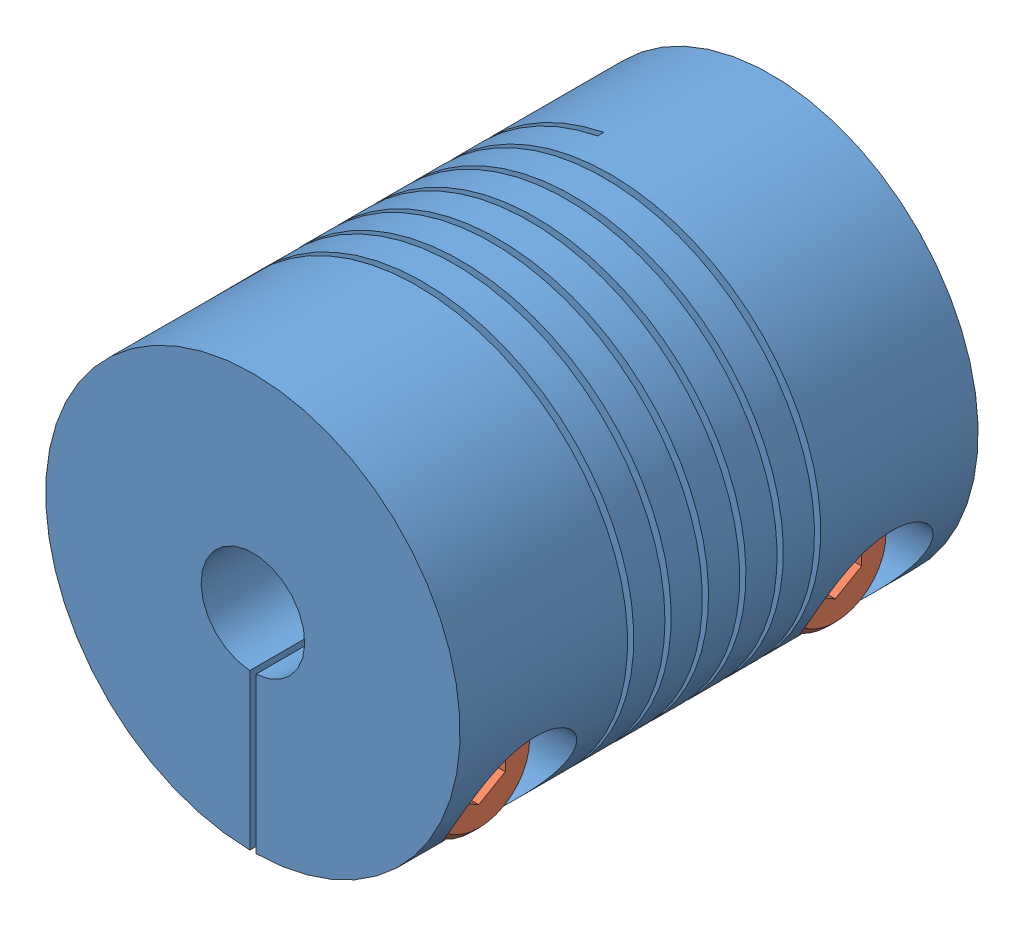
SolidWorks assembly Assem2, configuration Default. Lengths in mm.
Overall size (20.7 20.83 25).
3 component instances, 2 part files, 4 mates.
Components (placement in the parent):
- .25 inch x 5mm Flexible Coupling-1: .25 inch x 5mm Flexible Coupling [Default] at (-56.5603 -15.013 52.546) size (20.7 20.83 25)
- Socket Head Cap Screw_AM-1: Socket Head Cap Screw_AM [B18.3.1M - 3 x 0.5 x 12 Hex SHCS -- 12NHX] at (-49.5603 -20.013 48.646) x (-1 0 0) z (0 0 -1) size (15 5.5 5.5)
- Socket Head Cap Screw_AM-2: Socket Head Cap Screw_AM [B18.3.1M - 3 x 0.5 x 12 Hex SHCS -- 12NHX] at (-49.5603 -20.013 31.446) x (-1 0 0) z (0 0 -1) size (15 5.5 5.5)
Mates (geometry in assembly coordinates):
- Coincident1: coincident: plane of .25 inch x 5mm Flexible Coupling-1 through (-52.5603 -20.013 48.646) normal (1 0 0); plane of Socket Head Cap Screw_AM-1 through (-52.5603 -17.263 48.646) normal (-1 0 0)
- Concentric1: concentric aligned: cylinder of .25 inch x 5mm Flexible Coupling-1 through (-66.9118 -20.013 48.646) axis (1 0 0) radius 1.5; cylinder of Socket Head Cap Screw_AM-1 through (-17.8103 -20.013 48.646) axis (1 0 0) radius 1.5
- Coincident2: coincident: plane of .25 inch x 5mm Flexible Coupling-1 through (-52.5603 -20.013 31.446) normal (1 0 0); plane of Socket Head Cap Screw_AM-2 through (-52.5603 -17.263 31.446) normal (-1 0 0)
- Concentric2: concentric aligned: cylinder of .25 inch x 5mm Flexible Coupling-1 through (-66.9118 -20.013 31.446) axis (1 0 0) radius 1.5; cylinder of Socket Head Cap Screw_AM-2 through (-17.8103 -20.013 31.446) axis (1 0 0) radius 1.5
